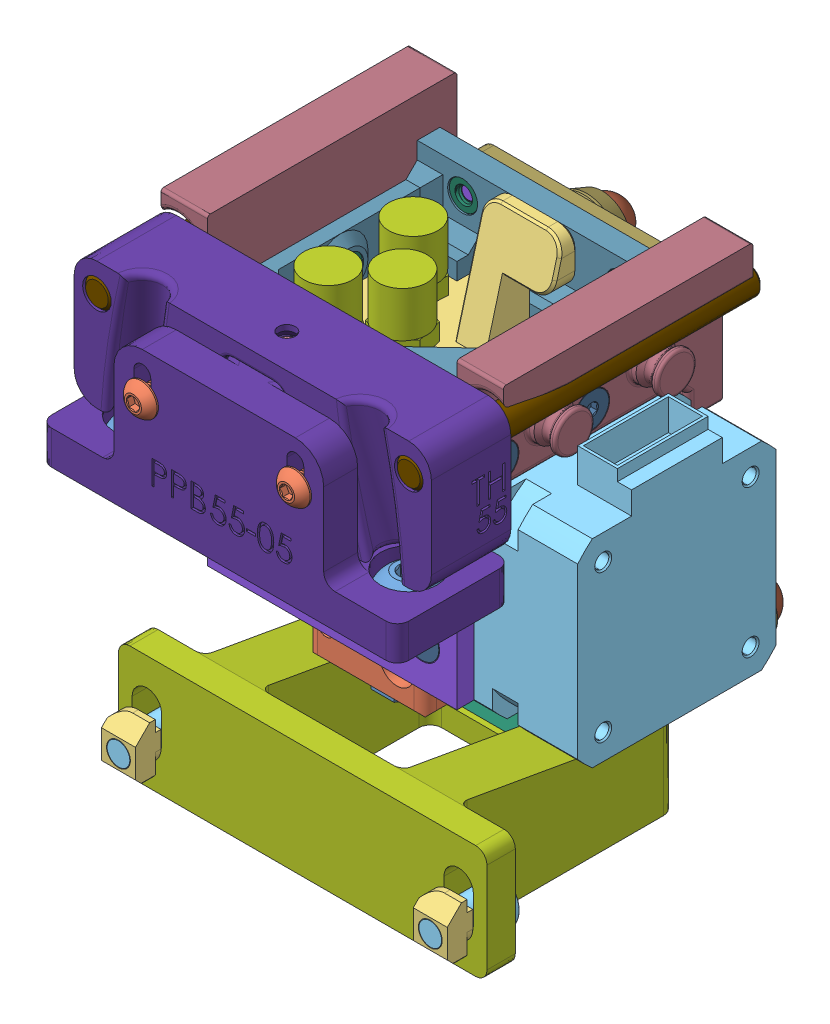
SolidWorks assembly Biqu H2O Tool Head, configuration Default. Lengths in mm.
Overall size (111.92 179.7 107.57).
72 component instances, 26 part files, 88 mates.
Components (placement in the parent):
- e3d nozzle-1: e3d nozzle [Default] at (0 2 0) size (8.08 12.5 7)
- h20 heating block-1: h20 heating block [Default] at (1.5 5 0) x (1 0 0) z (0 1 0) size (21 16 11.5)
- h2o body-1: h2o body [Default] at (10 37 -1.4) size (40 55 38)
- h2o side cover-1: h2o side cover [Default] at (-17.1 37 -1.4) x (0 1 0) z (1 0 0) size (35 35 2.1)
- h2o stepper-1: h2o stepper [Default] at (47 37 -1.4) x (-1 0 0) z (0 1 0) size (32 35 41)
- h2o throat-1: h2o throat [Default] at (0 11.5 0) x (0.921935 0 0.387345) z (0 1 0) size (6 6 24)
- fitting-1: fitting [Default] at (-7 57.5 -8.9) x (-0.54016 0 0.841562) z (0.841562 0 0.54016) size (8.6 15 9.24)
- fitting-2: fitting [Default] at (0 57.5 0) x (-0.289156 0 0.957282) z (0.957282 0 0.289156) size (8.6 15 9.24)
- fitting-3: fitting [Default] at (-7 57.5 6.1) x (-0.999978 0 0.006675) z (0.006675 0 0.999978) size (8.6 15 9.24)
- base_tool_plate_assembly-1: base_tool_plate_assembly [Default] at (-16.6504 -58.3782 -176.383) size (111.92 179.7 88.2)
  - m3_6mm_buttonhead_screw_92095A179-1: m3_6mm_buttonhead_screw_92095A179 [92095A179] at (49.3311 74.8782 156.133) x (-0.992968 0.118386 0) z (0 0 1) size (5.7 5.7 7.94)
  - wedge_plate-1: wedge_plate [Default] at (23.3504 89.8782 151.483) x (-1 0 0) z (0 0 1) size (28.78 26 5.61)
  - m3_6mm_flathead_screw_92125A126-1: m3_6mm_flathead_screw_92125A126 [92125A126] at (33.7427 83.8782 148.033) x (0.923728 0.383049 0) z (0 0 -1) size (6 6 6.28)
  - m3_6mm_flathead_screw_92125A126-2: m3_6mm_flathead_screw_92125A126 [92125A126] at (23.3504 101.8782 148.033) x (0.923728 0.383049 0) z (0 0 -1) size (6 6 6.28)
  - m3_6mm_flathead_screw_92125A126-3: m3_6mm_flathead_screw_92125A126 [92125A126] at (12.9581 83.8782 148.033) x (0.923728 0.383049 0) z (0 0 -1) size (6 6 6.28)
  - m3_threaded_ball-1: m3_threaded_ball [Default] at (1.28 74.0361 147.583) x (-0.210511 -0.977591 0) z (0 0 -1) size (8 8 7.78)
  - orbiter_base_tool_plate-1: orbiter_base_tool_plate [Tool Plate] at (23.3504 89.8782 151.483) size (102.25 179.33 88.2)
  - m3_threaded_ball-2: m3_threaded_ball [Default] at (51.3747 71.4396 147.583) x (-0.85964 -0.5109 0) z (0 0 -1) size (8 8 7.78)
  - m3_threaded_ball-3: m3_threaded_ball [Default] at (27.3352 120.2261 147.583) x (0.08699 -0.996209 0) z (0 0 -1) size (8 8 7.78)
  - m3_6mm_buttonhead_screw_92095A179-2: m3_6mm_buttonhead_screw_92095A179 [92095A179] at (-2.6304 74.8782 156.133) x (-0.992968 0.118386 0) z (0 0 1) size (5.7 5.7 7.94)
  - m3_6mm_buttonhead_screw_92095A179-3: m3_6mm_buttonhead_screw_92095A179 [92095A179] at (23.3504 119.8782 156.133) x (-0.992968 0.118386 0) z (0 0 1) size (5.7 5.7 7.94)
  - orbiter_base_tool_plate-2: orbiter_base_tool_plate [Tool Ball Cup] at (23.3504 89.8782 151.483) size (59.96 54.99 3.6)
  - orbiter_base_tool_plate-3: orbiter_base_tool_plate [Tool Ball Cup] at (49.3311 44.8782 151.483) size (59.96 54.99 3.6)
  - orbiter_base_tool_plate-4: orbiter_base_tool_plate [Tool Ball Cup] at (-2.6304 44.8782 151.483) size (59.96 54.99 3.6)
- tool_wings-3: tool_wings [Standard Left Tool Wing] at (-15.3 48.5 -24.9) x (0 0 1) z (-1 0 0) size (44.06 27 10.5)
- tool_wings-4: tool_wings [Standard Right Tool Wing] at (28.7 48.5 -24.9) x (0 0 1) z (-1 0 0) size (44.06 27 19.81)
- mount-1: mount [Default] at (6.7 54.5 -1.4) size (44 59 41)
- m3_heat_set_insert_94180A331-1: m3_heat_set_insert_94180A331 [94180A331] at (-7.3 64 -21.9) x (0.919441 0.393228 0) z (-0.393228 0.919441 0) size (5.56 4.12 5.56)
- m3_heat_set_insert_94180A331-2: m3_heat_set_insert_94180A331 [94180A331] at (20.7 64 -21.9) x (0.996241 -0.086621 0) z (0.086621 0.996241 0) size (5.56 4.12 5.56)
- m3_heat_set_insert_94180A331-3: m3_heat_set_insert_94180A331 [94180A331] at (20.7 13.5 -21.9) x (0.996241 -0.086621 0) z (0.086621 0.996241 0) size (5.56 4.12 5.56)
- m3_heat_set_insert_94180A331-4: m3_heat_set_insert_94180A331 [94180A331] at (-7.3 13.5 -21.9) x (0.996241 -0.086621 0) z (0.086621 0.996241 0) size (5.56 4.12 5.56)
- m3_heat_set_insert_94180A331-5: m3_heat_set_insert_94180A331 [94180A331] at (28.7 58.7 -1.9) x (0 0.450946 0.892551) z (0 0.892551 -0.450946) size (5.56 4.12 5.56)
- m3_heat_set_insert_94180A331-6: m3_heat_set_insert_94180A331 [94180A331] at (28.7 58.7 14.1) x (0 0.450946 0.892551) z (0 0.892551 -0.450946) size (5.56 4.12 5.56)
- m3_heat_set_insert_94180A331-7: m3_heat_set_insert_94180A331 [94180A331] at (-15.3 58.7 14.1) x (0 0.281892 -0.959446) z (0 0.959446 0.281892) size (5.56 4.12 5.56)
- m3_heat_set_insert_94180A331-8: m3_heat_set_insert_94180A331 [94180A331] at (-15.3 58.7 -1.9) x (0 0.281892 -0.959446) z (0 0.959446 0.281892) size (5.56 4.12 5.56)
- m3_6mm_flathead_screw_92125A126-1: m3_6mm_flathead_screw_92125A126 [92125A126] at (22.5 29.5 19.1) x (0.991332 0.131382 0) z (0 0 1) size (6 6 6.28)
- m3_6mm_flathead_screw_92125A126-2: m3_6mm_flathead_screw_92125A126 [92125A126] at (22.5 44.5 19.1) x (0.991332 0.131382 0) z (0 0 1) size (6 6 6.28)
- m3_6mm_flathead_screw_92125A126-4: m3_6mm_flathead_screw_92125A126 [92125A126] at (22.5 44.5 -21.9) x (-0.866294 0.499534 0) z (0 0 -1) size (6 6 6.28)
- m3_6mm_flathead_screw_92125A126-5: m3_6mm_flathead_screw_92125A126 [92125A126] at (22.5 29.5 -21.9) x (-0.998497 0.054803 0) z (0 0 -1) size (6 6 6.28)
- m3_6mm_buttonhead_screw_92095A179-1: m3_6mm_buttonhead_screw_92095A179 [92095A179] at (20.7 13.5 -26.55) x (0.717091 -0.69698 0) z (0 0 -1) size (5.7 5.7 7.94)
- m3_6mm_buttonhead_screw_92095A179-2: m3_6mm_buttonhead_screw_92095A179 [92095A179] at (-7.3 64 -26.55) x (0.717091 -0.69698 0) z (0 0 -1) size (5.7 5.7 7.94)
- m3_6mm_buttonhead_screw_92095A179-4: m3_6mm_buttonhead_screw_92095A179 [92095A179] at (20.7 64 -26.55) x (0.717091 -0.69698 0) z (0 0 -1) size (5.7 5.7 7.94)
- m3_6mm_buttonhead_screw_92095A179-5: m3_6mm_buttonhead_screw_92095A179 [92095A179] at (-7.3 13.5 -26.55) x (0.717091 -0.69698 0) z (0 0 -1) size (5.7 5.7 7.94)
- m3_6mm_flathead_screw_92125A126-7: m3_6mm_flathead_screw_92125A126 [92125A126] at (-18.1 58.7 14.1) x (0 0.290115 0.956992) z (-1 0 0) size (6 6 6.28)
- m3_6mm_flathead_screw_92125A126-8: m3_6mm_flathead_screw_92125A126 [92125A126] at (-18.1 58.7 -1.9) x (0 0.258248 0.966079) z (-1 0 0) size (6 6 6.28)
- m3_6mm_flathead_screw_92125A126-9: m3_6mm_flathead_screw_92125A126 [92125A126] at (31.5 58.7 -1.9) x (0 0.00234 -0.999997) z (1 0 0) size (6 6 6.28)
- m3_6mm_flathead_screw_92125A126-10: m3_6mm_flathead_screw_92125A126 [92125A126] at (31.5 58.7 14.1) x (0 0.014493 -0.999895) z (1 0 0) size (6 6 6.28)
- m3_12mm_buttohead_screw_92095A183-1: m3_12mm_buttohead_screw_92095A183 [92095A183] at (23.5 65.15 6.1) x (0.82363 0 -0.567127) z (0 1 0) size (5.7 5.7 13.97)
- m3_12mm_buttohead_screw_92095A183-3: m3_12mm_buttohead_screw_92095A183 [92095A183] at (23.5 65.15 -8.9) x (0.82363 0 -0.567127) z (0 1 0) size (5.7 5.7 13.97)
- adjustable_parking_post-1: adjustable_parking_post [Default] at (6.2959 -330.7019 -464.2157) size (63 34.68 67.77)
  - dovetail_parking_post-6: dovetail_parking_post [Parking Post Base] at (31.9041 374.0105 483.3157) x (-1 0 0) z (0 0 -1) size (63 26 20)
  - dowel_pin_5mm_d_60m_l-1: dowel_pin_5mm_d_60m_l [Default] at (27.9041 398.5105 437.3157) x (-0.987123 -0.159963 0) z (0 0 1) size (5 5 60)
  - dowel_pin_5mm_d_60m_l-2: dowel_pin_5mm_d_60m_l [Default] at (-27.0959 398.5105 437.3157) x (-0.123101 0.992394 0) z (0 0 1) size (5 5 60)
  - m5_8mm_buttonhead_screw_92095A207-1: m5_8mm_buttonhead_screw_92095A207 [92095A207] at (23.9041 379.7605 493.3157) x (0.778223 0 0.627988) z (0 1 0) size (9.5 9.5 11.02)
  - m5_8mm_buttonhead_screw_92095A207-2: m5_8mm_buttonhead_screw_92095A207 [92095A207] at (-23.0959 379.7605 493.3157) x (0.778223 0 0.627988) z (0 1 0) size (9.5 9.5 11.02)
  - m3_10mm_buttonhead_screw_92095A182-1: m3_10mm_buttonhead_screw_92095A182 [92095A182] at (13.9041 392.5105 504.9657) x (-0.866025 0.5 0) z (0 0 1) size (5.7 5.7 11.96)
  - m3_heat_set_insert_94180A331-1: m3_heat_set_insert_94180A331 [94180A331] at (13.9041 392.5105 497.3157) x (0.364827 0.931075 0) z (0.931075 -0.364827 0) size (5.56 4.12 5.56)
  - m5_locking_t_nut_20x20_generic-1: m5_locking_t_nut_20x20_generic [Default] at (-20.0959 369.0105 493.3157) x (0 0 1) z (-1 0 0) size (10 4.5 6)
  - m5_locking_t_nut_20x20_generic-2: m5_locking_t_nut_20x20_generic [Default] at (26.9041 369.0105 493.3157) x (0 0 1) z (-1 0 0) size (10 4.5 6)
  - dovetail_parking_post-4: dovetail_parking_post [Tool Holder] at (31.9041 372.5105 483.3157) x (-1 0 0) z (0 0 -1) size (63 22.68 14.1)
  - m3_heat_set_insert_94180A331-2: m3_heat_set_insert_94180A331 [94180A331] at (-13.0959 392.5105 497.3157) x (-0.287155 -0.957884 0) z (-0.957884 0.287155 0) size (5.56 4.12 5.56)
  - m3_10mm_buttonhead_screw_92095A182-2: m3_10mm_buttonhead_screw_92095A182 [92095A182] at (-13.0959 392.5105 504.9657) x (-0.757956 0.652306 0) z (0 0 1) size (5.7 5.7 11.96)
  - m3_heat_set_insert_94180A331-3: m3_heat_set_insert_94180A331 [94180A331] at (0.4041 400.0105 491.3157) x (-0.759723 0 0.650247) z (-0.650247 0 -0.759723) size (5.56 4.12 5.56)
  - m3_8mm_buttonhead_screw_92095A181-3: m3_8mm_buttonhead_screw_92095A181 [92095A181] at (0.4041 401.6605 491.3157) x (0.786316 0 0.617824) z (0 1 0) size (5.7 5.7 9.95)
- extruder_wiper_assembly-1: extruder_wiper_assembly [Default] at (-102.8455 -9.1541 -3.0477) x (-1 0 0) z (0 0 -1) size (65 20 48.17)
  - m5_low_profile_screw_template-1: m5_low_profile_screw_template [M5 x 10] at (-76.8455 -0.4194 -27.1477) x (0 0 -1) z (1 0 0) size (11.62 9 9)
  - m5_locking_t_nut_20x20_generic-1: m5_locking_t_nut_20x20_generic [Default] at (-128.8455 -0.4194 -27.1477) x (0 -1 0) z (-1 0 0) size (10 4.5 6)
  - m5_locking_t_nut_20x20_generic-2: m5_locking_t_nut_20x20_generic [Default] at (-73.8455 -0.4194 -27.1477) x (0 -1 0) z (-1 0 0) size (10 4.5 6)
  - m5_low_profile_screw_template-2: m5_low_profile_screw_template [M5 x 10] at (-131.8455 -0.4194 -27.1477) x (0 0 -1) z (1 0 0) size (11.62 9 9)
  - silicone_wiper-1: silicone_wiper [Default] at (-124.3455 -4.9194 13.8523) x (1 0 0) z (0 -1 0) size (40 3.17 15)
  - long_ooze_wiper_v1-1: long_ooze_wiper_v1 [Default] at (-116.8455 -7.9194 -22.1477) size (65 20 43.17)
- back spacer-1: back spacer [Default] at (22.7 37.25 16.1) size (44 30.5 3)
Mates (geometry in assembly coordinates):
- Coincident1: coincident anti-aligned: plane of h2o body-1 through (25 19.5 -18.9) normal (1 0 0); plane of h2o stepper-1 through (25 37 -1.4) normal (-1 0 0)
- Coincident2: coincident aligned: plane of h2o body-1 through (25 54.5 -18.9) normal (0 1 0); plane of h2o stepper-1 through (36.5 54.5 -16.3248) normal (0 1 0)
- Coincident3: coincident aligned: plane of h2o body-1 through (10 37 16.1) normal (0 0 1); plane of h2o stepper-1 through (36.5 51.9248 16.1) normal (0 0 1)
- Coincident7: coincident anti-aligned: plane of e3d nozzle-1 through (0 5 0) normal (0 1 0); plane of h20 heating block-1 through (1.5 5 0) normal (0 -1 0)
- Concentric1: concentric aligned: cylinder of e3d nozzle-1 through (0 5 0) axis (0 1 0) radius 3; cylinder of h20 heating block-1 through (0 16.5 0) axis (0 1 0) radius 2.5
- Parallel1: parallel aligned: plane of h20 heating block-1 through (-9 16.5 -8) normal (-1 0 0); plane of h2o side cover-1 through (-17.1 37 -1.4) normal (-1 0 0)
- Concentric2: concentric anti-aligned: cylinder of h20 heating block-1 through (0 16.5 0) axis (0 1 0) radius 2.5; cylinder of h2o throat-1 through (0 20 0) axis (0 -1 0) radius 3
- Tangent1: tangent: plane of h20 heating block-1 through (1.5 16.5 0) normal (0 1 0); circle of h2o throat-1
- Concentric3: concentric aligned: cylinder of h2o body-1 through (0 54.5 0) axis (0 -1 0) radius 3; cylinder of h2o throat-1 through (0 35.5 0) axis (0 -1 0) radius 3
- Concentric4: concentric: cylinder of h2o body-1 through (0 54.5 0) axis (0 -1 0) radius 3
- Parallel2: parallel aligned: plane of h2o body-1 through (25 54.5 -18.9) normal (0 1 0)
- Parallel3: parallel anti-aligned: plane of h2o side cover-1 through (-17.1 37 -1.4) normal (-1 0 0)
- Coincident9: coincident: plane of e3d nozzle-1 through (0 0 0) normal (0 -1 0)
- Coincident11: coincident anti-aligned: plane of h2o body-1 through (25 54.5 -18.9) normal (0 1 0); plane of fitting-1 through (-7 54.5 -8.9) normal (0 -1 0)
- Concentric5: concentric aligned: cylinder of h2o body-1 through (-7 50 -8.9) axis (0 1 0) radius 2.5; cylinder of fitting-1 through (-7 50.5 -8.9) axis (0 1 0) radius 2
- Coincident12: coincident anti-aligned: plane of h2o body-1 through (25 54.5 -18.9) normal (0 1 0); plane of fitting-3 through (-7 54.5 6.1) normal (0 -1 0)
- Concentric6: concentric aligned: cylinder of h2o body-1 through (-7 50 6.1) axis (0 1 0) radius 2.5; cylinder of fitting-3 through (-7 50.5 6.1) axis (0 1 0) radius 2
- Coincident13: coincident anti-aligned: plane of h2o body-1 through (25 54.5 -18.9) normal (0 1 0); plane of fitting-2 through (0 54.5 0) normal (0 -1 0)
- Concentric7: concentric anti-aligned: cylinder of h2o body-1 through (0 54.5 0) axis (0 -1 0) radius 2.5; cylinder of fitting-2 through (0 50.5 0) axis (0 1 0) radius 2
- Distance1: distance = 3 mm anti-aligned: plane of h2o body-1 through (-15 19.5 -18.9) normal (0 -1 0); plane of h20 heating block-1 through (1.5 16.5 0) normal (0 1 0)
- Coincident14: coincident anti-aligned: plane of h2o body-1 through (25 54.5 -18.9) normal (0 1 0); plane of tool_wings-3 through (-18.1 54.5 19.1) normal (0 -1 0)
- Tangent2: tangent aligned: cylinder of h2o body-1 through (14.5 39.5 4.6) axis (-1 0 0) radius 14.5; plane of tool_wings-3 through (-18.1 73.5 19.1) normal (0 0 1)
- Coincident19: coincident aligned: plane of tool_wings-3 through (-18.1 75.5 -24.9) normal (0 1 0); plane of tool_wings-4 through (31.5 75.5 -24.9) normal (0 1 0)
- Coincident20: coincident aligned: plane of tool_wings-3 through (-18.1 48.5 -24.9) normal (0 0 -1); plane of tool_wings-4 through (31.5 48.5 -24.9) normal (0 0 -1)
- Distance3: distance = 44 mm anti-aligned: plane of tool_wings-3 through (-15.3 48.5 -24.9) normal (1 0 0); plane of tool_wings-4 through (28.7 48.5 -24.9) normal (-1 0 0)
- Width1: width anti-aligned: plane of tool_wings-3 through (-15.3 48.5 -24.9) normal (1 0 0); plane of tool_wings-4 through (28.7 48.5 -24.9) normal (-1 0 0); plane of base_tool_plate_assembly-1/orbiter_base_tool_plate-1 through (-10.8 67.5 -21.9) normal (-1 0 0); plane of base_tool_plate_assembly-1/orbiter_base_tool_plate-1 through (24.2 67.5 -21.9) normal (1 0 0)
- Coincident24: coincident aligned: plane of h2o body-1 through (-15 19.5 -18.9) normal (0 -1 0); plane of h2o side cover-1 through (-15 19.5 13.6269) normal (0 -1 0)
- Coincident25: coincident aligned: plane of h2o body-1 through (10 37 16.1) normal (0 0 1); plane of h2o side cover-1 through (-15 52.0269 16.1) normal (0 0 1)
- Coincident26: coincident anti-aligned: plane of h2o body-1 through (-15 54.5 -18.9) normal (-1 0 0); plane of h2o side cover-1 through (-15 37 -1.4) normal (1 0 0)
- Distance5: distance = 3 mm anti-aligned: plane of base_tool_plate_assembly-1/orbiter_base_tool_plate-1 through (32.6808 16.5 -21.9) normal (0 0 1); plane of h2o body-1 through (10 37 -18.9) normal (0 0 -1)
- Coincident28: coincident aligned: plane of tool_wings-3 through (-18.1 73.5 19.1) normal (0 0 1); plane of mount-1 through (-15.3 57.5 19.1) normal (0 0 1)
- Width2: width anti-aligned: plane of tool_wings-4 through (28.7 48.5 -24.9) normal (-1 0 0); plane of mount-1 through (-15.3 48.5 -24.9) normal (1 0 0); plane of tool_wings-3 through (28.7 57.5 19.1) normal (1 0 0); plane of mount-1 through (-15.3 57.5 19.1) normal (-1 0 0)
- Coincident29: coincident anti-aligned: plane of h2o body-1 through (25 54.5 -18.9) normal (0 1 0); plane of mount-1 through (6.7 54.5 -1.4) normal (0 -1 0)
- Coincident30: coincident aligned: plane of mount-1 through (-15.3 57.5 -21.9) normal (0 0 -1); plane of m3_heat_set_insert_94180A331-1 through (-7.3 64 -21.9) normal (0 0 -1)
- Concentric8: concentric aligned: circle of mount-1; circle of m3_heat_set_insert_94180A331-1
- Coincident31: coincident aligned: plane of mount-1 through (-15.3 57.5 -21.9) normal (0 0 -1); plane of m3_heat_set_insert_94180A331-2 through (20.7 64 -21.9) normal (0 0 -1)
- Concentric9: concentric aligned: circle of mount-1; circle of m3_heat_set_insert_94180A331-2
- Coincident32: coincident aligned: plane of mount-1 through (-15.3 57.5 -21.9) normal (0 0 -1); plane of m3_heat_set_insert_94180A331-3 through (20.7 13.5 -21.9) normal (0 0 -1)
- Concentric10: concentric aligned: circle of mount-1; circle of m3_heat_set_insert_94180A331-3
- Coincident33: coincident aligned: plane of mount-1 through (-15.3 57.5 -21.9) normal (0 0 -1); plane of m3_heat_set_insert_94180A331-4 through (-7.3 13.5 -21.9) normal (0 0 -1)
- Concentric11: concentric aligned: circle of mount-1; circle of m3_heat_set_insert_94180A331-4
- Coincident34: coincident aligned: plane of mount-1 through (28.7 57.5 19.1) normal (1 0 0); plane of m3_heat_set_insert_94180A331-5 through (28.7 58.7 -1.9) normal (1 0 0)
- Coincident35: coincident aligned: plane of mount-1 through (28.7 57.5 19.1) normal (1 0 0); plane of m3_heat_set_insert_94180A331-5 through (28.7 58.7 -1.9) normal (1 0 0)
- Coincident36: coincident aligned: plane of mount-1 through (28.7 57.5 19.1) normal (1 0 0); plane of m3_heat_set_insert_94180A331-6 through (28.7 58.7 14.1) normal (1 0 0)
- Concentric12: concentric anti-aligned: circle of mount-1; circle of m3_heat_set_insert_94180A331-6
- Coincident37: coincident aligned: plane of mount-1 through (28.7 57.5 19.1) normal (1 0 0); plane of m3_heat_set_insert_94180A331-5 through (28.7 58.7 -1.9) normal (1 0 0)
- Concentric13: concentric anti-aligned: circle of mount-1; circle of m3_heat_set_insert_94180A331-5
- Coincident38: coincident aligned: plane of mount-1 through (-15.3 57.5 19.1) normal (-1 0 0); plane of m3_heat_set_insert_94180A331-7 through (-15.3 58.7 14.1) normal (-1 0 0)
- Concentric14: concentric aligned: circle of mount-1; circle of m3_heat_set_insert_94180A331-7
- Coincident39: coincident aligned: plane of mount-1 through (-15.3 57.5 19.1) normal (-1 0 0); plane of m3_heat_set_insert_94180A331-8 through (-15.3 58.7 -1.9) normal (-1 0 0)
- Concentric15: concentric aligned: circle of mount-1; circle of m3_heat_set_insert_94180A331-8
- Coincident40: coincident aligned: plane of mount-1 through (-15.3 57.5 19.1) normal (0 0 1); plane of m3_6mm_flathead_screw_92125A126-1 through (22.6971 28.013 19.1) normal (0 0 1)
- Coincident41: coincident aligned: plane of mount-1 through (-15.3 57.5 19.1) normal (0 0 1); plane of m3_6mm_flathead_screw_92125A126-2 through (22.6971 43.013 19.1) normal (0 0 1)
- Concentric16: concentric aligned: circle of m3_6mm_flathead_screw_92125A126-1; circle of back spacer-1
- Concentric17: concentric aligned: circle of m3_6mm_flathead_screw_92125A126-2; circle of back spacer-1
- Coincident42: coincident aligned: plane of mount-1 through (-15.3 57.5 -21.9) normal (0 0 -1); plane of m3_6mm_flathead_screw_92125A126-4 through (21.7507 43.2006 -21.9) normal (0 0 -1)
- Concentric18: concentric aligned: circle of mount-1; circle of m3_6mm_flathead_screw_92125A126-4
- Concentric19: concentric aligned: circle of mount-1; circle of m3_6mm_flathead_screw_92125A126-5
- Coincident43: coincident anti-aligned: plane of base_tool_plate_assembly-1/orbiter_base_tool_plate-1 through (32.6808 16.5 -24.9) normal (0 0 -1); plane of m3_6mm_buttonhead_screw_92095A179-1 through (22.6864 15.5437 -24.9) normal (0 0 1)
- Concentric20: concentric anti-aligned: circle of base_tool_plate_assembly-1/orbiter_base_tool_plate-1; circle of m3_6mm_buttonhead_screw_92095A179-1
- Coincident44: coincident anti-aligned: plane of base_tool_plate_assembly-1/orbiter_base_tool_plate-1 through (32.6808 16.5 -24.9) normal (0 0 -1); plane of m3_6mm_buttonhead_screw_92095A179-5 through (-5.3136 15.5437 -24.9) normal (0 0 1)
- Concentric21: concentric anti-aligned: circle of base_tool_plate_assembly-1/orbiter_base_tool_plate-1; circle of m3_6mm_buttonhead_screw_92095A179-5
- Coincident45: coincident anti-aligned: plane of base_tool_plate_assembly-1/orbiter_base_tool_plate-1 through (32.6808 16.5 -24.9) normal (0 0 -1); plane of m3_6mm_buttonhead_screw_92095A179-4 through (22.6864 66.0437 -24.9) normal (0 0 1)
- Concentric22: concentric anti-aligned: circle of base_tool_plate_assembly-1/orbiter_base_tool_plate-1; circle of m3_6mm_buttonhead_screw_92095A179-4
- Coincident46: coincident anti-aligned: plane of base_tool_plate_assembly-1/orbiter_base_tool_plate-1 through (32.6808 16.5 -24.9) normal (0 0 -1); plane of m3_6mm_buttonhead_screw_92095A179-2 through (-5.3136 66.0437 -24.9) normal (0 0 1)
- Concentric23: concentric anti-aligned: circle of base_tool_plate_assembly-1/orbiter_base_tool_plate-1; circle of m3_6mm_buttonhead_screw_92095A179-2
- Coincident47: coincident aligned: plane of tool_wings-3 through (-18.1 48.5 -24.9) normal (-1 0 0); plane of m3_6mm_flathead_screw_92125A126-7 through (-18.1 57.2645 14.5352) normal (-1 0 0)
- Coincident48: coincident aligned: plane of tool_wings-3 through (-18.1 48.5 -24.9) normal (-1 0 0); plane of m3_6mm_flathead_screw_92125A126-8 through (-18.1 57.2509 -1.5126) normal (-1 0 0)
- Concentric24: concentric aligned: circle of tool_wings-3; circle of m3_6mm_flathead_screw_92125A126-8
- Concentric25: concentric aligned: circle of tool_wings-3; circle of m3_6mm_flathead_screw_92125A126-7
- Coincident49: coincident aligned: plane of tool_wings-4 through (31.5 48.5 -24.9) normal (1 0 0); plane of m3_6mm_flathead_screw_92125A126-10 through (31.5 57.2002 14.0783) normal (1 0 0)
- Concentric26: concentric anti-aligned: circle of tool_wings-4; circle of m3_6mm_flathead_screw_92125A126-10
- Coincident50: coincident aligned: plane of tool_wings-4 through (31.5 48.5 -24.9) normal (1 0 0); plane of m3_6mm_flathead_screw_92125A126-9 through (31.5 57.2 -1.9035) normal (1 0 0)
- Concentric27: concentric anti-aligned: circle of tool_wings-4; circle of m3_6mm_flathead_screw_92125A126-9
- Coincident51: coincident anti-aligned: plane of mount-1 through (6.7 63.5 -1.4) normal (0 1 0); plane of m3_12mm_buttohead_screw_92095A183-1 through (25.1163 63.5 8.4473) normal (0 -1 0)
- Concentric28: concentric anti-aligned: cylinder of mount-1 through (23.5 57.5 6.1) axis (0 -1 0) radius 1.6; circle of m3_12mm_buttohead_screw_92095A183-1
- Coincident52: coincident anti-aligned: plane of mount-1 through (6.7 63.5 -1.4) normal (0 1 0); plane of m3_12mm_buttohead_screw_92095A183-3 through (25.1163 63.5 -6.5527) normal (0 -1 0)
- Concentric29: concentric anti-aligned: cylinder of mount-1 through (23.5 57.5 -8.9) axis (0 -1 0) radius 1.6; circle of m3_12mm_buttohead_screw_92095A183-3
- Width3: width anti-aligned: plane of adjustable_parking_post-1/dovetail_parking_post-4 through (-24.8 72.8086 -48.6791) normal (-1 0 0); plane of tool_wings-4 through (38.2 72.8086 -48.6791) normal (1 0 0); plane of adjustable_parking_post-1/dovetail_parking_post-4 through (31.5 48.5 -24.9) normal (1 0 0); plane of tool_wings-3 through (-18.1 48.5 -24.9) normal (-1 0 0)
- Coincident54: coincident anti-aligned: plane of mount-1 through (-15.3 57.5 19.1) normal (0 0 1); plane of adjustable_parking_post-1/dovetail_parking_post-4 through (38.2 47.8086 19.1) normal (0 0 -1)
- Coincident55: coincident: plane of h2o side cover-1 through (-17.1 37 -1.4) normal (-1 0 0); line of tool_wings-3 through (-17.1 54.5 16.8929) axis (0 0 -1)
- Coincident56: coincident aligned: plane of mount-1 through (-15.3 57.5 -21.9) normal (0 0 -1); plane of m3_6mm_flathead_screw_92125A126-5 through (22.4178 28.0023 -21.9) normal (0 0 -1)
- Coincident57: coincident anti-aligned: plane of adjustable_parking_post-1/dovetail_parking_post-6 through (38.2 49.3086 19.1) normal (0 0 -1); plane of extruder_wiper_assembly-1/long_ooze_wiper_v1-1 through (14 -17.0735 19.1) normal (0 0 1)
- Parallel4: parallel anti-aligned: plane of adjustable_parking_post-1/dovetail_parking_post-6 through (38.2 43.3086 19.1) normal (0 -1 0); plane of extruder_wiper_assembly-1/long_ooze_wiper_v1-1 through (14 2.9265 19.1) normal (0 1 0)
- Width4: width aligned: plane of extruder_wiper_assembly-1/long_ooze_wiper_v1-1 through (14 -17.0735 19.1) normal (-1 0 0); plane of h20 heating block-1 through (-11 -17.0735 19.1) normal (1 0 0); plane of extruder_wiper_assembly-1/long_ooze_wiper_v1-1 through (-9 16.5 -8) normal (-1 0 0); plane of h20 heating block-1 through (12 16.5 -8) normal (1 0 0)
- Coincident59: coincident aligned: plane of mount-1 through (28.7 57.5 19.1) normal (1 0 0); plane of back spacer-1 through (28.7 37.25 19.1) normal (1 0 0)
- Coincident60: coincident anti-aligned: plane of mount-1 through (6.7 52.5 -1.4) normal (0 -1 0); plane of back spacer-1 through (22.7 52.5 19.1) normal (0 1 0)
- Concentric30: concentric aligned: circle of m3_heat_set_insert_94180A331-3; circle of m3_6mm_buttonhead_screw_92095A179-1
